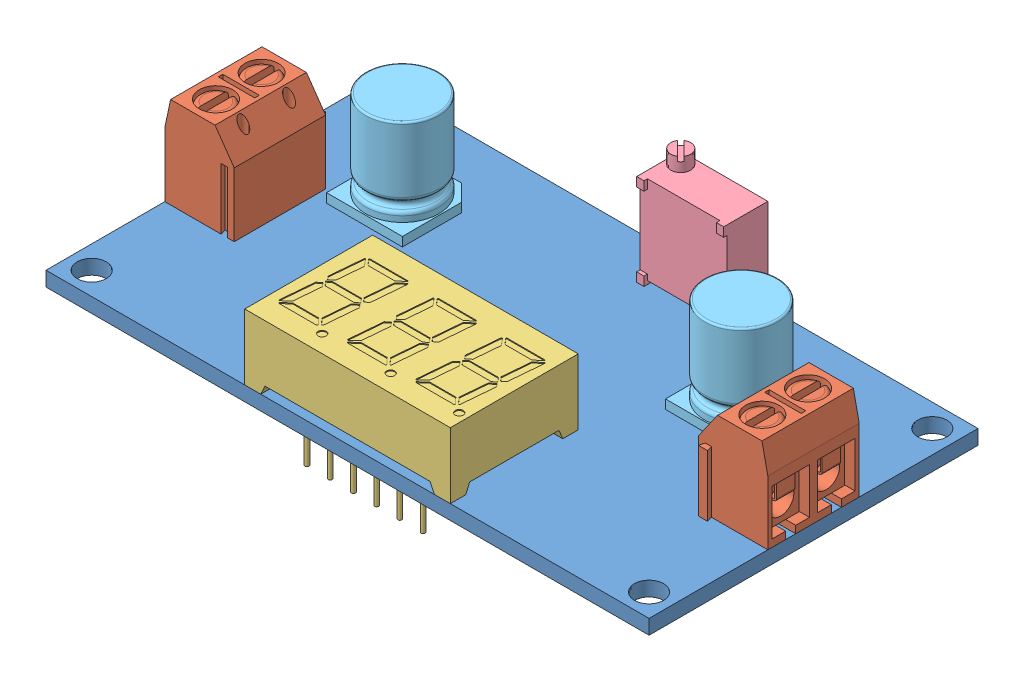
SolidWorks assembly LM2596 Buck Converter 4.0-40 to 1.3-37V, configuration Default. Lengths in mm.
Overall size (66 17.65 36).
7 component instances, 5 part files, 19 mates.
Components (placement in the parent):
- BASE,  LM2596 Buck Converter 4.0-40 to 1.3-37V-1: BASE,  LM2596 Buck Converter 4.0-40 to 1.3-37V [Default] at origin size (66 1.6 36)
- DG301-5.0-02, LM2596 Buck Converter 4.0-40 to 1.3-37V-3: DG301-5.0-02, LM2596 Buck Converter 4.0-40 to 1.3-37V [Default] at (29.9 1.6 2.5) x (0 0 -1) z (0 1 0) size (10.6 7.6 14.3)
- DG301-5.0-02, LM2596 Buck Converter 4.0-40 to 1.3-37V-2: DG301-5.0-02, LM2596 Buck Converter 4.0-40 to 1.3-37V [Default] at (-29.9 1.6 -2.5) x (0 0 1) z (0 1 0) size (10.6 7.6 14.3)
- 3 DIGIT 7 SEGMENT DISPLAY, LM2596 Buck Converter 4.0-40 to 1.3-37V-1: 3 DIGIT 7 SEGMENT DISPLAY, LM2596 Buck Converter 4.0-40 to 1.3-37V [Default] at (0 8.8 11) size (22.5 13.3 14)
- Trimpot 3296W, LM2596 Buck Converter 4.0-40 to 1.3-37V-1: Trimpot 3296W, LM2596 Buck Converter 4.0-40 to 1.3-37V [Valor predeterminado] at (5.235 1.6 -15.585) x (-1 0 0) z (0 1 0) size (9.53 4.83 14.15)
- 220 35V CAPACITOR, LM2596 Buck Converter 4.0-40 to 1.3-37V-1: 220 35V CAPACITOR, LM2596 Buck Converter 4.0-40 to 1.3-37V [Default] at (-19.85 1.6 -7.85) size (8.3 10.5 8.3)
- 220 35V CAPACITOR, LM2596 Buck Converter 4.0-40 to 1.3-37V-2: 220 35V CAPACITOR, LM2596 Buck Converter 4.0-40 to 1.3-37V [Default] at (18.25 1.6 -6.85) size (8.3 10.5 8.3)
Mates (geometry in assembly coordinates):
- Coincident1: coordinate: point of BASE,  LM2596 Buck Converter 4.0-40 to 1.3-37V-1
- Coincident2: coincident anti-aligned: plane of BASE,  LM2596 Buck Converter 4.0-40 to 1.3-37V-1 through (0 1.6 0) normal (0 1 0); plane of DG301-5.0-02, LM2596 Buck Converter 4.0-40 to 1.3-37V-2 through (-25.4 1.6 5) normal (0 -1 0)
- Coincident3: coincident anti-aligned: plane of BASE,  LM2596 Buck Converter 4.0-40 to 1.3-37V-1 through (0 1.6 0) normal (0 1 0); plane of DG301-5.0-02, LM2596 Buck Converter 4.0-40 to 1.3-37V-3 through (25.4 1.6 -5) normal (0 -1 0)
- Coincident4: coincident aligned: plane of BASE,  LM2596 Buck Converter 4.0-40 to 1.3-37V-1 through (-33 1.6 -18) normal (-1 0 0); plane of DG301-5.0-02, LM2596 Buck Converter 4.0-40 to 1.3-37V-2 through (-33 1.6 5) normal (-1 0 0)
- Coincident5: coincident aligned: plane of BASE,  LM2596 Buck Converter 4.0-40 to 1.3-37V-1 through (33 1.6 -18) normal (1 0 0); plane of DG301-5.0-02, LM2596 Buck Converter 4.0-40 to 1.3-37V-3 through (33 1.6 -5) normal (1 0 0)
- Coincident6: coincident aligned: plane of DG301-5.0-02, LM2596 Buck Converter 4.0-40 to 1.3-37V-3 through (29.9 1.6 5) normal (0 0 1); plane of DG301-5.0-02, LM2596 Buck Converter 4.0-40 to 1.3-37V-2 through (-29.9 1.6 5) normal (0 0 1)
- Width1: width anti-aligned: plane of BASE,  LM2596 Buck Converter 4.0-40 to 1.3-37V-1 through (-33 1.6 -18) normal (0 0 -1); plane of BASE,  LM2596 Buck Converter 4.0-40 to 1.3-37V-1 through (-33 1.6 18) normal (0 0 1); plane of DG301-5.0-02, LM2596 Buck Converter 4.0-40 to 1.3-37V-2 through (-29.9 1.6 5) normal (0 0 1); plane of DG301-5.0-02, LM2596 Buck Converter 4.0-40 to 1.3-37V-2 through (-29.9 1.6 -5) normal (0 0 -1)
- Coincident7: coincident anti-aligned: plane of BASE,  LM2596 Buck Converter 4.0-40 to 1.3-37V-1 through (0 1.6 0) normal (0 1 0); plane of 3 DIGIT 7 SEGMENT DISPLAY, LM2596 Buck Converter 4.0-40 to 1.3-37V-1 through (-11.25 1.6 18) normal (0 -1 0)
- Coincident8: coincident aligned: plane of BASE,  LM2596 Buck Converter 4.0-40 to 1.3-37V-1 through (-33 1.6 18) normal (0 0 1); plane of 3 DIGIT 7 SEGMENT DISPLAY, LM2596 Buck Converter 4.0-40 to 1.3-37V-1 through (-11.25 1.6 18) normal (0 0 1)
- Coincident9: coincident aligned: plane of 3 DIGIT 7 SEGMENT DISPLAY, LM2596 Buck Converter 4.0-40 to 1.3-37V-1 through (0 8.8 11) normal (1 0 0)
- Coincident10: coincident anti-aligned: plane of BASE,  LM2596 Buck Converter 4.0-40 to 1.3-37V-1 through (0 1.6 0) normal (0 1 0); plane of Trimpot 3296W, LM2596 Buck Converter 4.0-40 to 1.3-37V-1 through (10 1.6 -13.17) normal (0 -1 0)
- Coincident11: coincident aligned: plane of BASE,  LM2596 Buck Converter 4.0-40 to 1.3-37V-1 through (-33 1.6 -18) normal (0 0 -1); plane of Trimpot 3296W, LM2596 Buck Converter 4.0-40 to 1.3-37V-1 through (5.235 1.6 -18) normal (0 0 -1)
- Distance1: distance = 23 mm aligned: plane of Trimpot 3296W, LM2596 Buck Converter 4.0-40 to 1.3-37V-1 through (10 11.63 -13.17) normal (1 0 0); plane of BASE,  LM2596 Buck Converter 4.0-40 to 1.3-37V-1 through (33 1.6 -18) normal (1 0 0)
- Coincident12: coincident anti-aligned: plane of BASE,  LM2596 Buck Converter 4.0-40 to 1.3-37V-1 through (0 1.6 0) normal (0 1 0); plane of 220 35V CAPACITOR, LM2596 Buck Converter 4.0-40 to 1.3-37V-1 through (-19.85 1.6 -7.85) normal (0 -1 0)
- Coincident13: coincident aligned: plane of 220 35V CAPACITOR, LM2596 Buck Converter 4.0-40 to 1.3-37V-1 through (-19.85 12.1 -7.85) normal (0 1 0); plane of 220 35V CAPACITOR, LM2596 Buck Converter 4.0-40 to 1.3-37V-2 through (18.25 12.1 -6.85) normal (0 1 0)
- Distance2: distance = 6 mm aligned: plane of BASE,  LM2596 Buck Converter 4.0-40 to 1.3-37V-1 through (-33 1.6 -18) normal (0 0 -1); plane of 220 35V CAPACITOR, LM2596 Buck Converter 4.0-40 to 1.3-37V-1 through (-24 2.6 -12) normal (0 0 -1)
- Distance3: distance = 7 mm aligned: plane of BASE,  LM2596 Buck Converter 4.0-40 to 1.3-37V-1 through (-33 1.6 -18) normal (0 0 -1); plane of 220 35V CAPACITOR, LM2596 Buck Converter 4.0-40 to 1.3-37V-2 through (14.1 2.6 -11) normal (0 0 -1)
- Distance4: distance = 9 mm aligned: plane of BASE,  LM2596 Buck Converter 4.0-40 to 1.3-37V-1 through (-33 1.6 -18) normal (-1 0 0); plane of 220 35V CAPACITOR, LM2596 Buck Converter 4.0-40 to 1.3-37V-1 through (-24 2.6 -12) normal (-1 0 0)
- Distance5: distance = 10.6 mm aligned: plane of 220 35V CAPACITOR, LM2596 Buck Converter 4.0-40 to 1.3-37V-2 through (22.4 2.6 -11) normal (1 0 0); plane of BASE,  LM2596 Buck Converter 4.0-40 to 1.3-37V-1 through (33 1.6 -18) normal (1 0 0)
